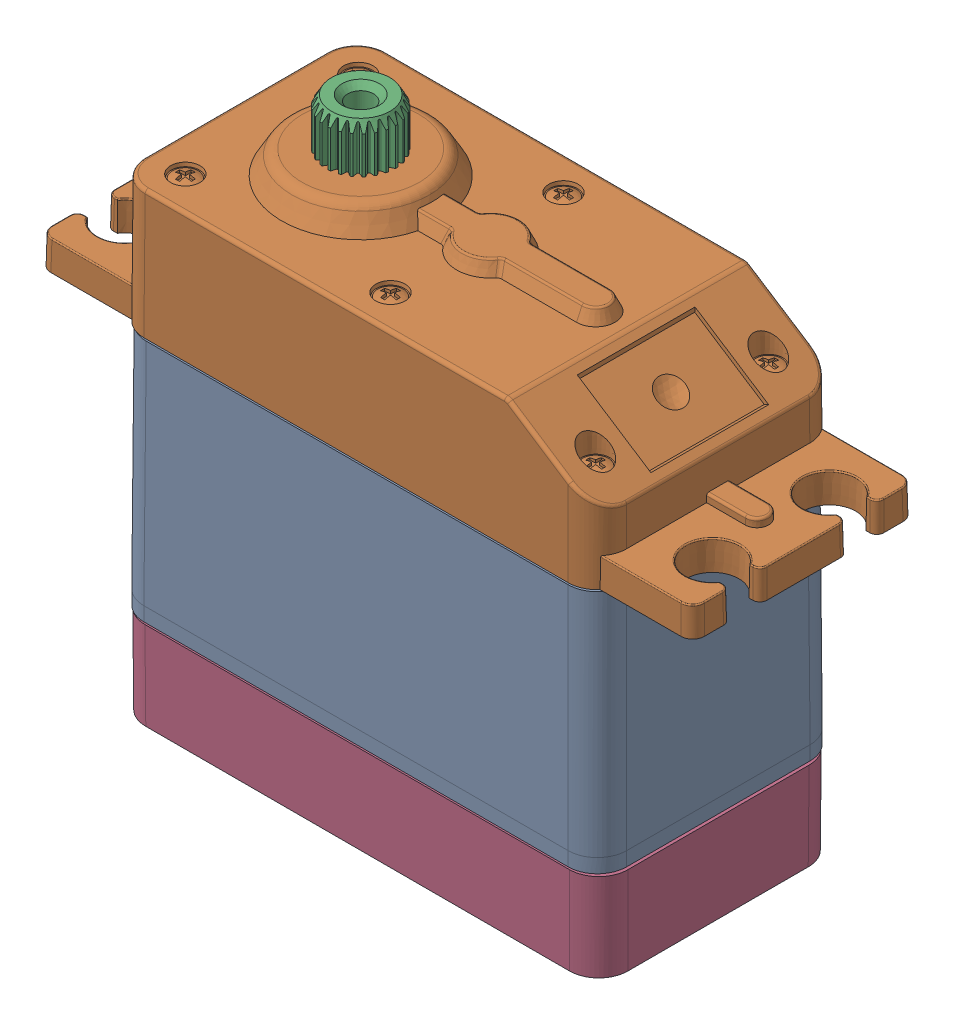
SolidWorks assembly 431_ASM_21_ASM, configuration 默认. Lengths in mm.
Overall size (55.9 52.75 20.7).
5 component instances, 4 part files, 0 mates.
Components (placement in the parent):
- MIDDLE-SHELL_2-1: MIDDLE-SHELL_2 [默认] at origin size (41.3 20.8 20.7)
- UPPER-SHELL_2-1: UPPER-SHELL_2 [默认] at (0 19.85 0) size (55.9 12.95 20.7)
- FIVE-STAGE-GEAR_ASM_1_ASM-1: FIVE-STAGE-GEAR_ASM_1_ASM [默认] at (-9.95 26.55 0) x (0 -1 0) z (-0.029666 0 0.99956) size (5 5.96 5.95)
  - FIVE-STAGE-GEAR_2-1: FIVE-STAGE-GEAR_2 [默认] x (0 0 -1) z (-1 0 0) size (5.95 5.96 5)
- 430-431-HUO-GAI_4-1: 430-431-HUO-GAI_4 [默认] at (0 16.7 0) size (41.33 16.25 20.5)
